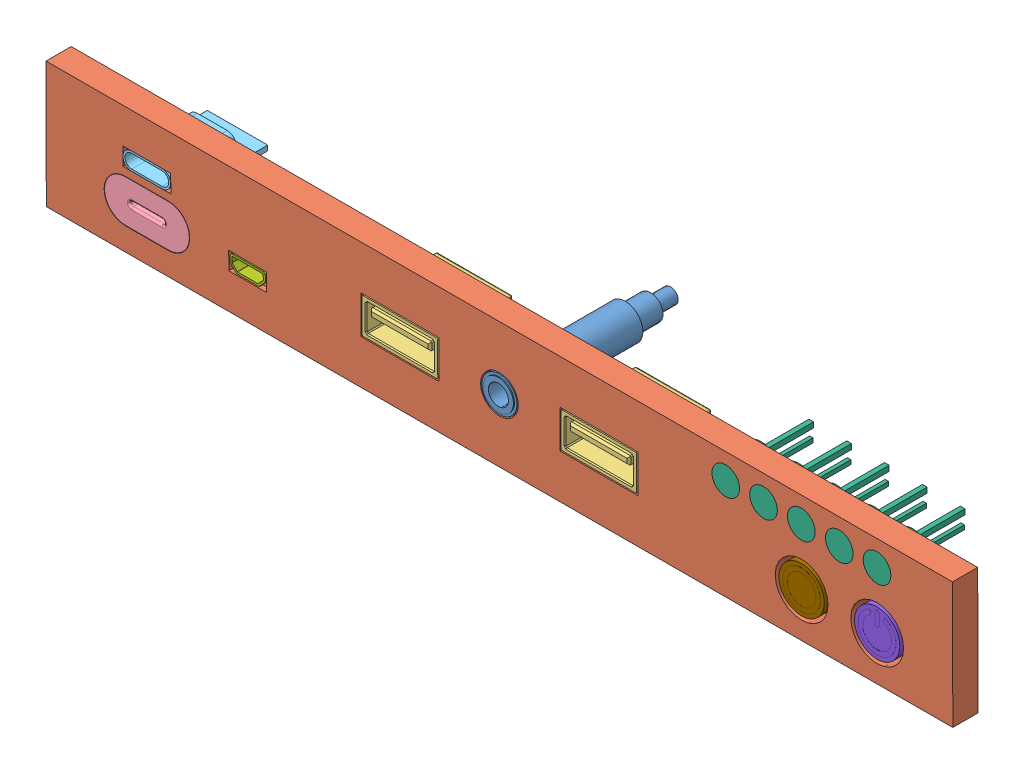
SolidWorks assembly FrontIO, configuration Default. Lengths in mm.
Overall size (180.06 25.43 34.2).
14 component instances, 9 part files, 26 mates.
Components (placement in the parent):
- aux-jack-1: aux-jack [Default] at (22.4107 22.4035 9.9667) size (7 7 34.2)
- Front-1: Front [Default] at (22.4107 22.4035 29.9667) x (0.999997 0.002406 0) z (0.002406 -0.999997 0) size (180 5 25)
- USB-Port-1: USB-Port [Default] at (42.1606 22.451 19.9667) x (0.999997 0.002406 0) z (0 0 1) size (15 7 15)
- USB-Port-2: USB-Port [Default] at (2.6608 22.356 19.9667) x (0.999997 0.002406 0) z (0 0 1) size (15 7 15)
- Lightning-c-1: Lightning-c [Default] at (-51.7901 21.1486 19.9667) x (0.999997 0.002406 0) z (0 0 1) size (17 8.5 15)
- usb-c-port-1: usb-c-port [Default] at (-47.5981 25.9851 21.9667) x (0.999997 0.002406 0) z (0 0 1) size (12 4.5 18)
- LeD-1: LeD [Default] at (97.3924 30.0839 28.9667) size (6.5 6.5 17)
- LeD-2: LeD [Default] at (89.8925 30.0659 28.9667) size (6.5 6.5 17)
- LeD-3: LeD [Default] at (82.3501 30.0477 28.9667) size (6.5 6.5 17)
- LeD-4: LeD [Default] at (74.8501 30.0297 28.9667) size (6.5 6.5 17)
- LeD-5: LeD [Default] at (67.3501 30.0116 28.9667) size (6.5 6.5 17)
- USB-b-1: USB-b [Default] at (-27.5801 18.5332 28.9667) x (0.999997 0.002406 0) z (0 0 1) size (11 4 9)
- PWR-1: PWR [Default] at (97.4195 18.8339 31.9667) size (9 9 9.01)
- CHG-1: CHG [Default] at (82.4195 18.7979 31.9667) size (9 9 9.01)
Mates (geometry in assembly coordinates):
- Concentric1: concentric aligned: circle of aux-jack-1; circle of Front-1
- Coincident1: coincident aligned: plane of aux-jack-1 through (22.4107 22.4035 34.9667) normal (0 0 1); plane of Front-1 through (22.4107 22.4035 34.9667) normal (0 0 1)
- Distance4: distance = 0.25 mm anti-aligned: plane of Front-1 through (-5.0802 18.5874 34.9667) normal (-0.002406 0.999997 0); plane of USB-Port-2 through (-4.8308 18.838 34.9667) normal (0.002406 -0.999997 0)
- Distance3: distance = 0.25 mm anti-aligned: plane of Front-1 through (49.9196 18.7197 34.9667) normal (-0.002406 0.999997 0); plane of USB-Port-1 through (34.6691 18.933 34.9667) normal (0.002406 -0.999997 0)
- Distance2: distance = 0.25 mm anti-aligned: plane of Front-1 through (10.4198 18.6246 34.9667) normal (-0.999997 -0.002406 0); plane of USB-Port-2 through (10.1523 25.874 34.9667) normal (0.999997 0.002406 0)
- Distance1: distance = 0.25 mm anti-aligned: plane of Front-1 through (49.9196 18.7197 34.9667) normal (-0.999997 -0.002406 0); plane of USB-Port-1 through (49.6522 25.969 34.9667) normal (0.999997 0.002406 0)
- Coincident6: coincident aligned: plane of Front-1 through (22.4107 22.4035 34.9667) normal (0 0 1); plane of USB-Port-1 through (42.1606 22.451 34.9667) normal (0 0 1)
- Coincident7: coincident aligned: plane of Front-1 through (22.4107 22.4035 34.9667) normal (0 0 1); plane of USB-Port-2 through (2.6608 22.356 34.9667) normal (0 0 1)
- Coincident8: coincident: plane of Front-1 through (22.4107 22.4035 34.9667) normal (0 0 1); plane of Lightning-c-1 through (-43.3291 18.5185 34.9667) normal (0 0 1)
- Coincident9: coincident: plane of Front-1 through (-51.8199 14.2471 34.9667) normal (-0.002406 0.999997 0); plane of Lightning-c-1 through (-51.8209 14.2471 34.9667) normal (0.002406 -0.999997 0)
- Coincident10: coincident: cylinder of Front-1 through (-43.3301 18.5175 34.9667) axis (0 0 -1) radius 4.25; line of Lightning-c-1 through (-39.0802 18.5288 34.8667) axis (0 0 -1)
- Coincident11: coincident: plane of Front-1 through (22.4107 22.4035 34.9667) normal (0 0 1); plane of usb-c-port-1 through (-44.5971 25.9933 34.9667) normal (0 0 1)
- Coincident12: coincident: plane of Front-1 through (-52.3439 24.2237 34.9667) normal (-0.002406 0.999997 0); plane of usb-c-port-1 through (-50.5949 24.2279 34.9667) normal (0.002406 -0.999997 0)
- Coincident13: coincident: plane of Front-1 through (-42.8439 24.2465 34.9667) normal (-0.999997 -0.002406 0); line of usb-c-port-1 through (-42.8481 25.9975 34.9667) axis (0 0 -1)
- Coincident14: coincident aligned: circle of Front-1; circle of LeD-1
- Coincident15: coincident aligned: circle of Front-1; circle of LeD-2
- Coincident16: coincident aligned: circle of Front-1; circle of LeD-3
- Coincident17: coincident aligned: circle of Front-1; circle of LeD-4
- Coincident18: coincident aligned: circle of Front-1; circle of LeD-5
- Coincident19: coincident: plane of Front-1 through (22.4107 22.4035 34.9667) normal (0 0 1); plane of USB-b-1 through (-27.5801 18.5332 34.9667) normal (0 0 1)
- Distance5: distance = 0.25 mm: plane of USB-b-1 through (-31.0837 20.0248 34.9667) normal (-0.999997 -0.002406 0); plane of Front-1 through (-31.3259 16.7742 34.9667) normal (0.999997 0.002406 0)
- Distance6: distance = 0.25 mm anti-aligned: plane of USB-b-1 through (-31.0837 20.0248 34.9667) normal (-0.002406 0.999997 0); plane of Front-1 through (-31.3343 20.2742 34.9667) normal (0.002406 -0.999997 0)
- Coincident20: coincident: plane of Front-1 through (22.4107 22.4035 34.9667) normal (0 0 1); plane of CHG-1 through (82.4195 18.7979 34.9667) normal (0 0 1)
- Concentric2: concentric aligned: circle of Front-1; circle of CHG-1
- Concentric3: concentric: circle of Front-1; circle of PWR-1
- Coincident21: coincident aligned: plane of Front-1 through (22.4107 22.4035 34.9667) normal (0 0 1); plane of PWR-1 through (97.4195 18.8339 34.9667) normal (0 0 1)
